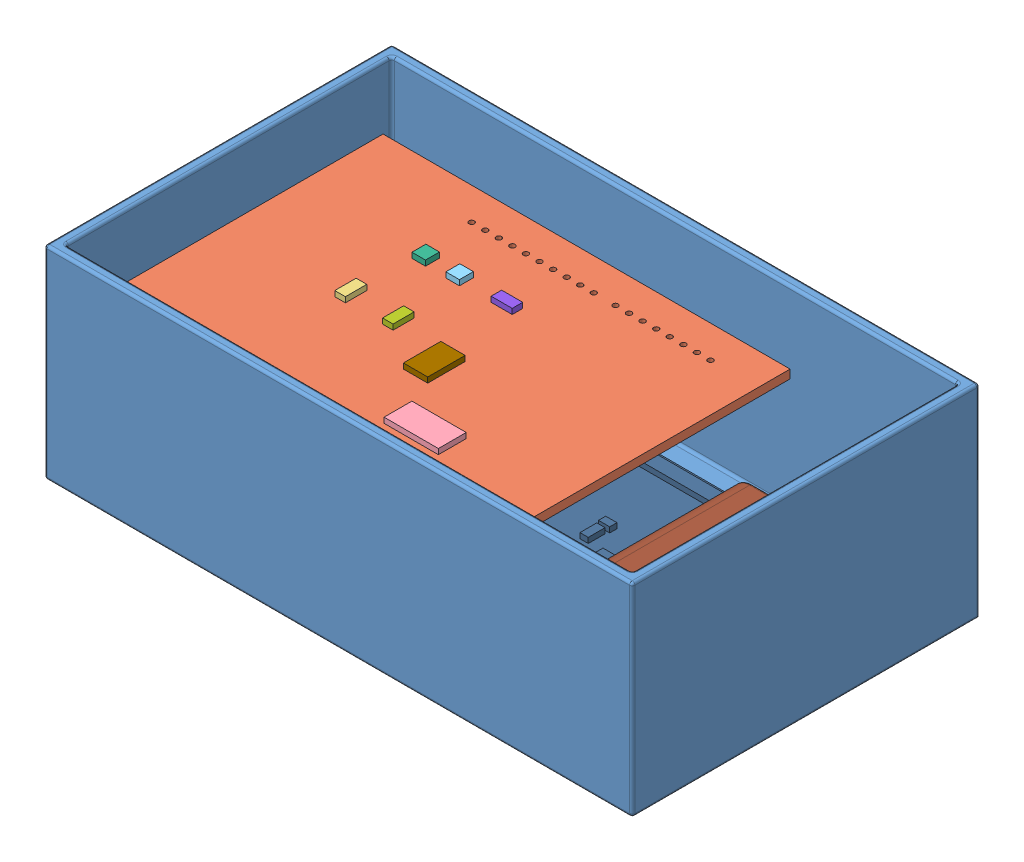
SolidWorks assembly final_assembly, configuration Default. Lengths in mm.
Overall size (125.39 38 89.75).
15 component instances, 14 part files, 10 mates.
Components (placement in the parent):
- case-1: case [Default] at (13.7194 36.5378 98.4027) size (110 38 65)
- initial_schematic_2-1: initial_schematic_2 [Default] at (-61.6588 61.1378 135.7739) size (99.2 26.2 86.11)
  - initial_schematic-1: initial_schematic [Default] x (1 0 0) z (0 1 0) size (76.18 59.36 1.6)
  - C0805_C1_C0805-1: C0805_C1_C0805 [Default] at (57.15 1.6 -41.91) x (0 0 -1) z (0 1 0) size (4 1.99 1)
  - AB9V_AB9V-1: AB9V_AB9V [Default] at (86.36 1.6 -26.67) x (0 0 -1) z (0 1 0) size (5.21 10.16 1)
  - 1X01_JP1_1X01-1: 1X01_JP1_1X01 [Default] at (64.77 1.6 -54.61) x (1 0 0) z (0 1 0) size (2.54 2.62 1)
  - 1X01_JP2_1X01-1: 1X01_JP2_1X01 [Default] at (58.42 1.6 -54.61) x (1 0 0) z (0 1 0) size (2.54 2.62 1)
  - R0805W_50000-1: R0805W_50000 [Default] at (66.04 1.6 -41.91) x (0 0 1) z (0 1 0) size (3.95 1.97 1)
  - R0805W_200-1: R0805W_200 [Default] at (73.66 1.6 -54.61) x (1 0 0) z (0 1 0) size (3.95 1.97 1)
  - BTN_CK_KSS_SW1_BTN_CK_KSS-1: BTN_CK_KSS_SW1_BTN_CK_KSS [Default] at (76.2 1.6 -38.1) x (0 0 -1) z (0 1 0) size (7 4.55 1)
  - arduino_uno_rev3-02-th-1: arduino_uno_rev3-02-th [Default] at (38.092 -22.6 -14.0446) x (1 0 0) z (0 1 0) size (89.77 77.71 3.6)
- Part45^final_assembly-1: Part45^final_assembly [Default] at origin (virtual)
- Battery 9V-1: Battery 9V [Default] at (66.8887 32.7897 116.8631) x (1 0 0) z (0 1 0) size (25.91 48.13 16.26)
- Part46^final_assembly-1: Part46^final_assembly [Default] at origin (virtual)
- Part47^final_assembly-1: Part47^final_assembly [Default] at (66.8887 54.7938 116.8631) x (1 0 0) z (0 1 0) (virtual)
Mates (geometry in assembly coordinates):
- Coincident1: coincident: plane of case-1 through (13.7194 38.5378 98.4027) normal (0 1 0); plane of initial_schematic_2-1/arduino_uno_rev3-02-th-1 through (-23.5668 38.5378 121.7293) normal (0 -1 0)
- Coincident2: coincident: plane of case-1 through (-27.3688 38.5378 63.3439) normal (1 0 0); plane of initial_schematic_2-1/initial_schematic-1 through (-27.3688 62.7378 64.9839) normal (-1 0 0)
- Coincident3: coincident: plane of case-1 through (-27.3688 38.5378 124.3439) normal (0 0 -1); plane of initial_schematic_2-1/initial_schematic-1 through (-27.3688 62.7378 124.3439) normal (0 0 1)
- Coincident5: coincident: plane of case-1 through (78.6312 38.5378 63.3439) normal (-1 0 0); plane of Battery 9V-1 through (78.6312 38.5378 79.1319) normal (1 0 0)
- Coincident6: coincident: plane of case-1 through (-27.3688 38.5378 124.3439) normal (0 0 -1); plane of Battery 9V-1 through (52.7232 54.7938 124.3439) normal (0 0 1)
- Coincident7: coincident: plane of case-1 through (13.7194 38.5378 98.4027) normal (0 1 0); plane of Battery 9V-1 through (52.7232 38.5378 79.1319) normal (0 -1 0)
- InPlace1: in place: plane of Battery 9V-1 through (52.7232 54.7938 79.1319) normal (0 1 0); plane of ? through (0 54.7938 0) normal (0 1 0); moOrthogonalPlaneRef_w of Battery 9V-1 through (52.7232 54.7938 79.1319) normal (0 1 0); plane of ? through (0 54.7938 0) normal (0 0 -1); plane of Battery 9V-1 through (52.7232 54.7938 79.1319) normal (0 1 0); plane of ? through (0 54.7938 0) normal (1 0 0); plane of Battery 9V-1 through (52.7232 54.7938 79.1319) normal (0 1 0); unknown of Part47^final_assembly-1
- Coincident8: coincident: plane of Battery 9V-1; plane of ?
- Coincident9: coincident: moOrthogonalPlaneRef_w of Battery 9V-1 through (66.8887 54.7938 116.8631) normal (0 0 -1); plane of Part47^final_assembly-1 through (66.8887 54.7938 116.8631) normal (0 0 -1)
- Coincident10: coincident: moOrthogonalPlaneRef_w of Battery 9V-1 through (66.8887 54.7938 116.8631) normal (-1 0 0); plane of Part47^final_assembly-1 through (66.8887 54.7938 116.8631) normal (1 0 0)
